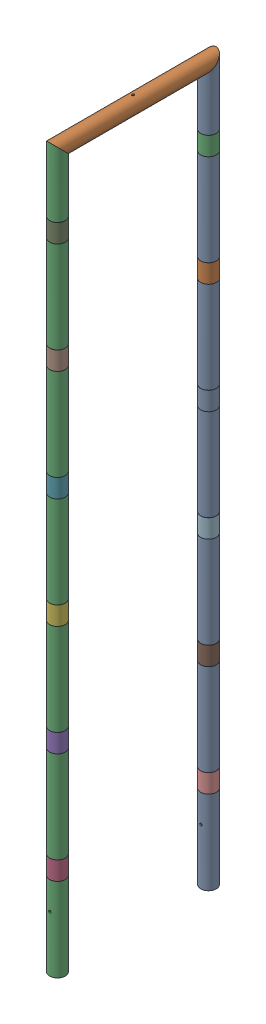
SolidWorks assembly GE-15023_ASM, configuration Default. Lengths in mm.
Overall size (42.42 1971.67 455.17).
15 component instances, 3 part files, 0 mates.
Components (placement in the parent):
- GE-15023-01-1: GE-15023-01 [Default] at origin size (42.16 1971.67 42.16)
- GE-15023-02-1: GE-15023-02 [Default] at (0 1950.593 206.375) x (1 0 0) z (0 1 0) size (42.16 454.91 42.16)
- GE-15023-01-2: GE-15023-01 [Default] at (0 0 412.75) x (-1 0 0) z (0 0 -1) size (42.16 1971.67 42.16)
- GE-15023-03-1: GE-15023-03 [Default] at (0 228.6 412.75) size (42.42 50.8 42.42)
- GE-15023-03-2: GE-15023-03 [Default] at (0 530.225 412.75) size (42.42 50.8 42.42)
- GE-15023-03-3: GE-15023-03 [Default] at (0 831.85 412.75) size (42.42 50.8 42.42)
- GE-15023-03-4: GE-15023-03 [Default] at (0 1133.475 412.75) size (42.42 50.8 42.42)
- GE-15023-03-5: GE-15023-03 [Default] at (0 1435.1 412.75) size (42.42 50.8 42.42)
- GE-15023-03-6: GE-15023-03 [Default] at (0 1736.725 412.75) size (42.42 50.8 42.42)
- GE-15023-03-7: GE-15023-03 [Default] at (0 228.6 0) size (42.42 50.8 42.42)
- GE-15023-03-8: GE-15023-03 [Default] at (0 530.225 0) size (42.42 50.8 42.42)
- GE-15023-03-9: GE-15023-03 [Default] at (0 831.85 0) size (42.42 50.8 42.42)
- GE-15023-03-10: GE-15023-03 [Default] at (0 1133.475 0) size (42.42 50.8 42.42)
- GE-15023-03-11: GE-15023-03 [Default] at (0 1435.1 0) size (42.42 50.8 42.42)
- GE-15023-03-12: GE-15023-03 [Default] at (0 1736.725 0) size (42.42 50.8 42.42)
